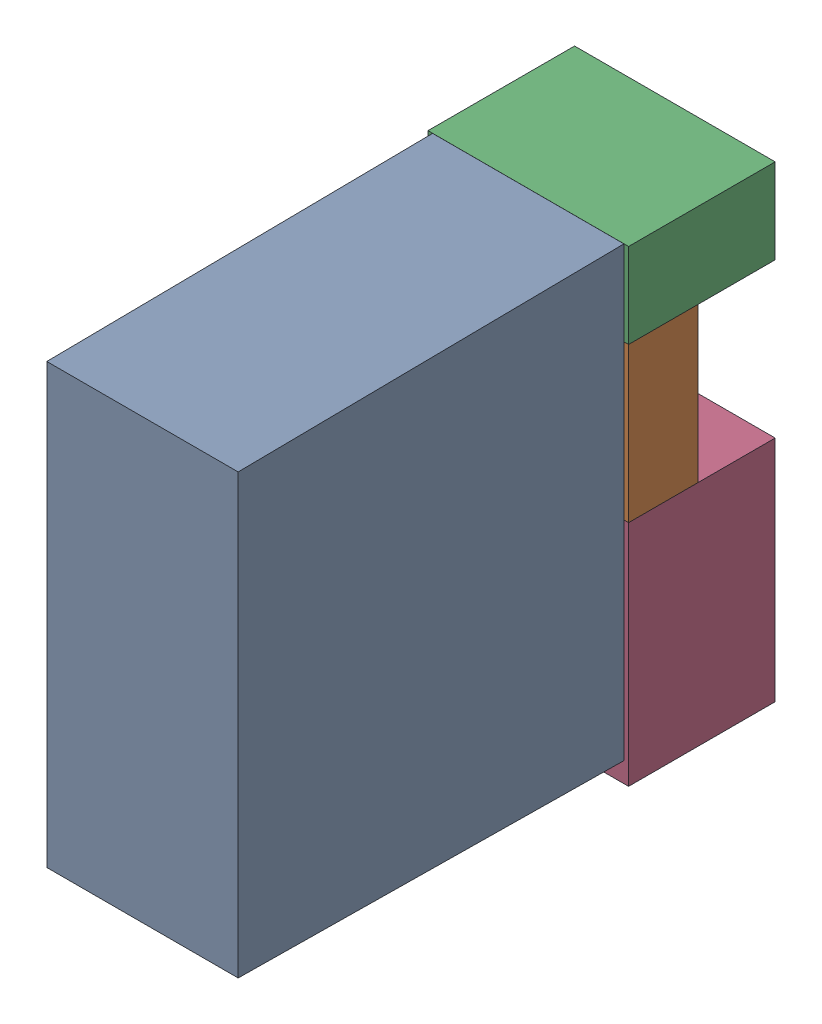
SolidWorks assembly K14, configuration Default. Lengths in mm.
Overall size (13 30.3 34.5).
7 component instances, 4 part files, 0 mates.
Components (placement in the parent):
- relais_40_61_8_006_0000-1: relais_40_61_8_006_0000 [Default] at (210.185 15.7216 9.5) x (0 1 0) z (1 0 0) size (29 30 12.4)
- 1151725064-1: 1151725064 [Default] at (210.185 34.225 5) size (13 10 4.5)
  - Extruded_3-1: Extruded_3 [Default] at origin size (13 10 4.5)
- 1151724928-1: 1151724928 [Default] at (210.185 41.975 0) size (13 5.5 9.5)
  - Extruded_2-1: Extruded_2 [Default] at origin size (13 5.5 9.5)
- 1151724792-1: 1151724792 [Default] at (210.185 21.825 0) size (13 14.8 9.5)
  - Extruded_4-1: Extruded_4 [Default] at origin size (13 14.8 9.5)
